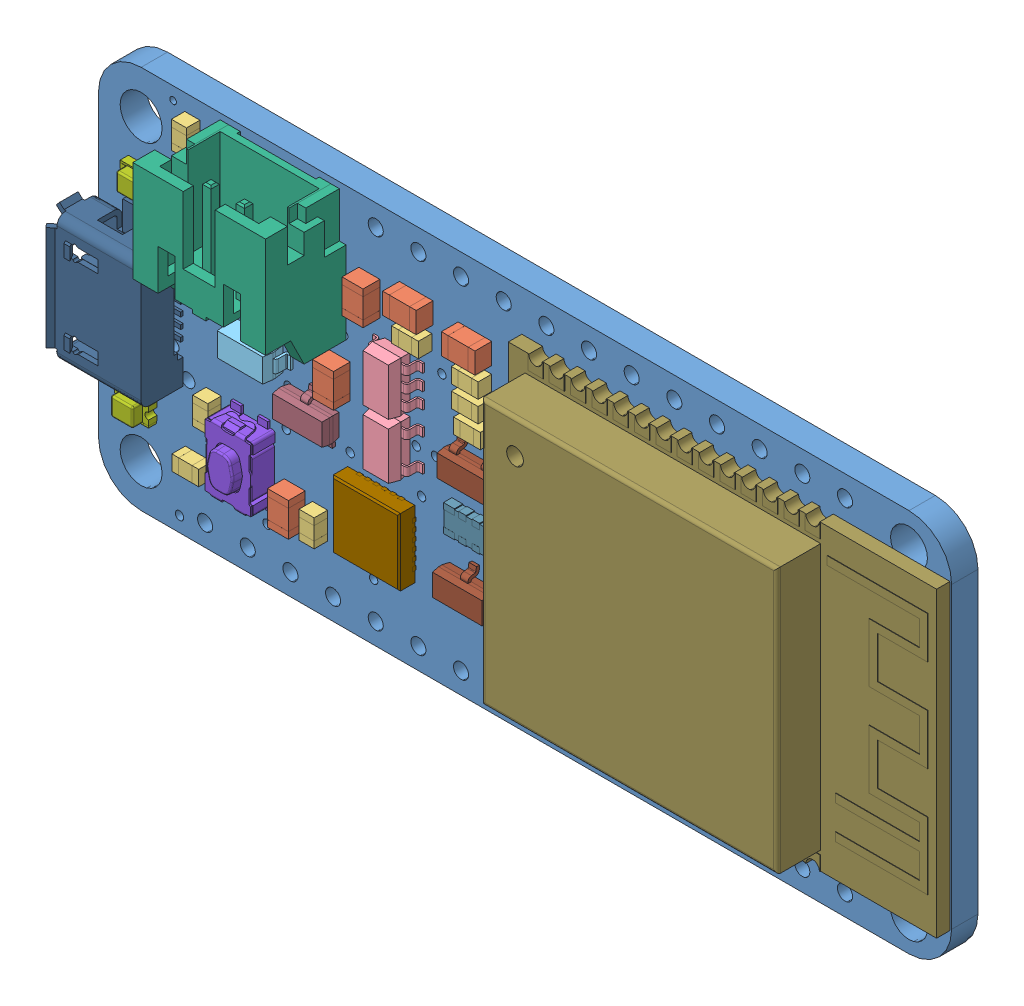
SolidWorks assembly huzzah32.stp, configuration Default. Lengths in mm.
Overall size (51.35 22.86 6.37).
30 component instances, 14 part files, 0 mates.
Components (placement in the parent):
- PCB Component.stp-1: PCB Component.stp [Default] at origin size (51.35 22.86 6.37)
  - Board.stp-1: Board.stp [Default] at origin size (50.8 22.86 1.57)
  - 10uF.stp-1: 10uF.stp [Default] at (18.918 18.883 1.57) x (-1 0 0) z (0 0 1) size (2 1.25 1)
  - 10uF.stp-2: 10uF.stp [Default] at (14.366 12.894 1.57) x (0 -1 0) z (0 0 1) size (2 1.25 1)
  - 10uF.stp-3: 10uF.stp [Default] at (16.129 18.034 1.57) x (0 -1 0) z (0 0 1) size (2 1.25 1)
  - 10uF.stp-4: 10uF.stp [Default] at (22.416 18.542 1.57) x (-1 0 0) z (0 0 1) size (2 1.25 1)
  - 10uF.stp-5: 10uF.stp [Default] at (11.684 4.902 1.57) x (0 -1 0) z (0 0 1) size (2 1.25 1)
  - 4.7K.stp-1: 4.7K.stp [Default] at (13.191 4.775 1.57) x (0 -1 0) z (0 0 1) size (1.6 0.9 0.8)
  - 4.7K.stp-2: 4.7K.stp [Default] at (5.969 4.191 1.57) size (1.6 0.9 0.8)
  - 4.7K.stp-3: 4.7K.stp [Default] at (5.588 21.082 1.57) x (0 -1 0) z (0 0 1) size (1.6 0.9 0.8)
  - 4.7K.stp-4: 4.7K.stp [Default] at (19.05 17.336 1.57) size (1.6 0.9 0.8)
  - 4.7K.stp-5: 4.7K.stp [Default] at (7.493 13.716 1.57) size (1.6 0.9 0.8)
  - 4.7K.stp-6: 4.7K.stp [Default] at (22.606 15.748 1.57) x (-1 0 0) z (0 0 1) size (1.6 0.9 0.8)
  - 4.7K.stp-7: 4.7K.stp [Default] at (22.606 17.018 1.57) size (1.6 0.9 0.8)
  - 4.7K.stp-8: 4.7K.stp [Default] at (6.858 7.493 1.57) x (0 -1 0) z (0 0 1) size (1.6 0.9 0.8)
  - 4.7K.stp-9: 4.7K.stp [Default] at (22.733 14.478 1.57) x (-1 0 0) z (0 0 1) size (1.6 0.9 0.8)
  - MCP73831T-2ACI_OT.stp-1: MCP73831T-2ACI_OT.stp [Default] at (17.907 14.859 1.57) x (0 1 0) z (0 0 1) size (3 3 1.4)
  - MCP73831T-2ACI_OT.stp-2: MCP73831T-2ACI_OT.stp [Default] at (17.907 11.557 1.57) x (0 -1 0) z (0 0 1) size (3 3 1.4)
  - MBR120.stp-1: MBR120.stp [Default] at (9.779 12.192 1.57) x (-1 0 0) z (0 0 1) size (3.6 1.4 1.35)
  - JSTPH.stp-1: JSTPH.stp [Default] at (10.795 19.304 1.57) size (7.9 8.6 4.8)
  - RED.stp-1: RED.stp [Default] at (2.413 5.588 1.57) x (0 -1 0) z (0 0 1) size (1.25 2.02 1.1)
  - RED.stp-2: RED.stp [Default] at (2.858 17.336 1.57) x (0 1 0) z (0 0 1) size (1.25 2.02 1.1)
  - KMR2.stp-1: KMR2.stp [Default] at (9.144 6.223 1.57) x (0 -1 0) z (0 0 1) size (4.6 2.8 1.94)
  - CP2104.stp-1: CP2104.stp [Default] at (16.891 6.477 1.57) size (4 4 1)
  - 20329.stp-1: 20329.stp [Default] at (4.445 11.43 1.57) x (0 -1 0) z (0 0 1) size (8.8 5.6 3)
  - mmbt2222.stp-1: mmbt2222.stp [Default] at (22.758 12.256 1.57) x (-1 0 0) z (0 0 1) size (3.04 2.64 1.12)
  - mmbt2222.stp-2: mmbt2222.stp [Default] at (22.479 5.969 1.57) size (3.04 2.64 1.12)
  - ESP32_WROOM32_SKINNY.stp-1: ESP32_WROOM32_SKINNY.stp [Default] at (38.354 11.43 1.57) x (0 -1 0) z (0 0 1) size (18 25.5 3.4)
  - DMG3415U.stp-1: DMG3415U.stp [Default] at (12.954 10.414 1.57) size (3.04 2.64 1.12)
  - 10K.stp-1: 10K.stp [Default] at (22.542 9.144 1.57) size (3.05 1.6 0.5)
